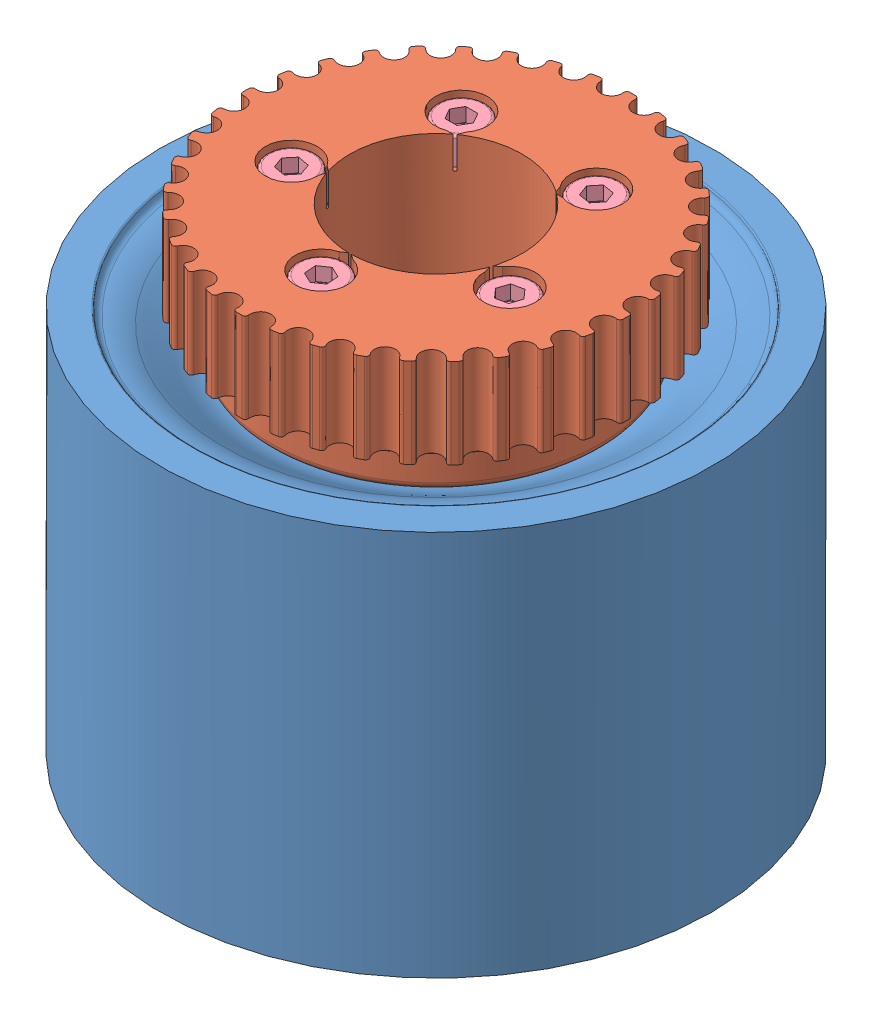
SolidWorks assembly Wheel Assy, configuration Standard. Lengths in mm.
Overall size (80 69 80).
13 component instances, 5 part files, 26 mates.
Components (placement in the parent):
- Orangatang Kegel 83mm Longboard Wheel-1: Orangatang Kegel 83mm Longboard Wheel [Default] at origin size (80 56 80)
- HTD Parametric Pulley-1: HTD Parametric Pulley [36T 13mm] at (0 31.6628 0) x (-0.809017 0 -0.587785) z (-0.587785 0 0.809017) size (56.01 36.18 56.01)
- Orangatang Kegel Flat Face-1: Orangatang Kegel Flat Face [Reshaped - to be tested] at (0 -25.3378 0) size (44 16.93 44)
- DIN 912 M4x60-1: DIN 912 M4x60 [DIN 912 M4 x 60] at (-9.7896 31.0628 -13.4742) x (0 -1 0) z (0 0 1) size (64 7 7)
- DIN 912 M4x60-2: DIN 912 M4x60 [DIN 912 M4 x 60] at (9.7896 31.0628 -13.4742) x (0 -1 0) z (-0.162886 0 0.986645) size (64 7 7)
- DIN 912 M4x60-3: DIN 912 M4x60 [DIN 912 M4 x 60] at (15.8398 30.8628 5.1467) x (0 -1 0) z (0.948955 0 0.315412) size (64 7 7)
- DIN 912 M4x60-4: DIN 912 M4x60 [DIN 912 M4 x 60] at (0 31.0628 16.655) x (0 -1 0) z (0.996968 0 -0.077808) size (64 7 7)
- DIN 912 M4x60-5: DIN 912 M4x60 [DIN 912 M4 x 60] at (-15.8398 31.0628 5.1467) x (0 -1 0) z (-0.173405 0 0.984851) size (64 7 7)
- prevailing torque nut style 1 insert_din-1: prevailing torque nut style 1 insert_din [DIN EN ISO 7040 - M4] at (-15.8398 -28.2378 5.1467) x (0.490805 0 -0.87127) z (0 -1 0) size (7 8.08 6)
- prevailing torque nut style 1 insert_din-2: prevailing torque nut style 1 insert_din [DIN EN ISO 7040 - M4] at (-9.7896 -28.2378 -13.4742) x (0.933211 0 -0.359329) z (0 -1 0) size (7 8.08 6)
- prevailing torque nut style 1 insert_din-3: prevailing torque nut style 1 insert_din [DIN EN ISO 7040 - M4] at (0 -28.2378 16.655) x (0.96783 0 -0.251605) z (0 -1 0) size (7 8.08 6)
- prevailing torque nut style 1 insert_din-4: prevailing torque nut style 1 insert_din [DIN EN ISO 7040 - M4] at (15.8398 -28.2378 5.1467) x (0.061225 0 -0.998124) z (0 -1 0) size (7 8.08 6)
- prevailing torque nut style 1 insert_din-5: prevailing torque nut style 1 insert_din [DIN EN ISO 7040 - M4] at (9.7896 -28.2378 -13.4742) x (0.981006 0 -0.193977) z (0 -1 0) size (7 8.08 6)
Mates (geometry in assembly coordinates):
- Konzentrisch1: concentric anti-aligned: cylinder of Orangatang Kegel 83mm Longboard Wheel-1 through (0 18.6628 0) axis (0 1 0) radius 11; cylinder of HTD Parametric Pulley-1 through (0 18.6628 0) axis (0 -1 0) radius 12.5
- Konzentrisch2: concentric aligned: cylinder of Orangatang Kegel 83mm Longboard Wheel-1 through (-15.0742 18.6628 -4.8979) axis (0 -1 0) radius 2.9; cylinder of HTD Parametric Pulley-1 through (-15.0742 31.6638 -4.8979) axis (0 -1 0) radius 2.85
- Deckungsgleich1: coincident anti-aligned: circle of Orangatang Kegel 83mm Longboard Wheel-1; circle of HTD Parametric Pulley-1
- Konzentrisch3: concentric anti-aligned: cylinder of Orangatang Kegel 83mm Longboard Wheel-1 through (0 18.6628 0) axis (0 1 0) radius 9.75; cylinder of Orangatang Kegel Flat Face-1 through (0 -32.3378 0) axis (0 -1 0) radius 12.5
- Konzentrisch4: concentric aligned: cylinder of Orangatang Kegel 83mm Longboard Wheel-1 through (-15.0742 18.6628 -4.8979) axis (0 -1 0) radius 2.9; cylinder of Orangatang Kegel Flat Face-1 through (-15.0742 -8.4032 -4.8979) axis (0 -1 0) radius 2.85
- Tangential1: tangent: circle of Orangatang Kegel 83mm Longboard Wheel-1; face of Orangatang Kegel Flat Face-1
- Konzentrisch6: concentric anti-aligned: cylinder of HTD Parametric Pulley-1 through (-9.7896 31.6628 -13.4742) axis (0 -1 0) radius 2.1; cylinder of DIN 912 M4x60-1 through (-9.7896 62.8128 -13.4742) axis (0 1 0) radius 2
- Konzentrisch7: concentric anti-aligned: cylinder of HTD Parametric Pulley-1 through (9.7896 31.6628 -13.4742) axis (0 -1 0) radius 2.1; cylinder of DIN 912 M4x60-2 through (9.7896 62.8128 -13.4742) axis (0 1 0) radius 2
- Konzentrisch8: concentric anti-aligned: cylinder of HTD Parametric Pulley-1 through (15.8398 31.6628 5.1467) axis (0 -1 0) radius 2.1; cylinder of DIN 912 M4x60-3 through (15.8398 62.6128 5.1467) axis (0 1 0) radius 2
- Konzentrisch9: concentric anti-aligned: cylinder of HTD Parametric Pulley-1 through (0 31.6628 16.655) axis (0 -1 0) radius 2.1; cylinder of DIN 912 M4x60-4 through (0 62.8128 16.655) axis (0 1 0) radius 2
- Konzentrisch10: concentric anti-aligned: cylinder of HTD Parametric Pulley-1 through (-15.8398 31.6628 5.1467) axis (0 -1 0) radius 2.1; cylinder of DIN 912 M4x60-5 through (-15.8398 62.8128 5.1467) axis (0 1 0) radius 2
- Deckungsgleich3: coincident anti-aligned: plane of HTD Parametric Pulley-1 through (0 27.0628 0) normal (0 1 0); plane of DIN 912 M4x60-1 through (-6.2896 27.0628 -13.4742) normal (0 -1 0)
- Deckungsgleich4: coincident anti-aligned: plane of HTD Parametric Pulley-1 through (0 27.0628 0) normal (0 1 0); plane of DIN 912 M4x60-5 through (-12.3929 27.0628 5.7536) normal (0 -1 0)
- Deckungsgleich5: coincident anti-aligned: plane of HTD Parametric Pulley-1 through (0 27.0628 0) normal (0 1 0); plane of DIN 912 M4x60-4 through (-0.2723 27.0628 13.1656) normal (0 -1 0)
- Deckungsgleich6: coincident aligned: plane of HTD Parametric Pulley-1 through (0 26.8628 0) normal (0 1 0); circle of DIN 912 M4x60-3
- Deckungsgleich7: coincident anti-aligned: plane of HTD Parametric Pulley-1 through (0 27.0628 0) normal (0 1 0); plane of DIN 912 M4x60-2 through (13.2428 27.0628 -12.9041) normal (0 -1 0)
- Konzentrisch11: concentric anti-aligned: cylinder of DIN 912 M4x60-1 through (-9.7896 62.8128 -13.4742) axis (0 1 0) radius 2; cylinder of DIN EN ISO 7040 M4-2 through (-9.7896 -25.3378 -13.4742) axis (0 -1 0) radius 1.65
- Konzentrisch12: concentric anti-aligned: cylinder of DIN 912 M4x60-5 through (-15.8398 62.8128 5.1467) axis (0 1 0) radius 2; cylinder of DIN EN ISO 7040 M4-1 through (-15.8398 -25.3378 5.1467) axis (0 -1 0) radius 1.65
- Konzentrisch13: concentric anti-aligned: cylinder of DIN EN ISO 7040 M4-3 through (0 -25.3378 16.655) axis (0 -1 0) radius 1.65; cylinder of DIN 912 M4x60-4 through (0 62.8128 16.655) axis (0 1 0) radius 2
- Konzentrisch14: concentric anti-aligned: cylinder of DIN 912 M4x60-3 through (15.8398 62.6128 5.1467) axis (0 1 0) radius 2; cylinder of DIN EN ISO 7040 M4-4 through (15.8398 -25.3378 5.1467) axis (0 -1 0) radius 1.65
- Konzentrisch15: concentric anti-aligned: cylinder of DIN EN ISO 7040 M4-5 through (9.7896 -25.3378 -13.4742) axis (0 -1 0) radius 1.65; cylinder of DIN 912 M4x60-2 through (9.7896 62.8128 -13.4742) axis (0 1 0) radius 2
- Deckungsgleich8: coincident aligned: plane of DIN EN ISO 7040 M4-4 through (19.8737 -25.3378 5.3941) normal (0 1 0); plane of DIN EN ISO 7040 M4-5 through (10.5735 -25.3378 -9.5095) normal (0 1 0)
- Deckungsgleich9: coincident aligned: plane of DIN EN ISO 7040 M4-2 through (-8.3374 -25.3378 -9.7027) normal (0 1 0); plane of DIN EN ISO 7040 M4-5 through (10.5735 -25.3378 -9.5095) normal (0 1 0)
- Deckungsgleich10: coincident aligned: plane of DIN EN ISO 7040 M4-3 through (1.0168 -25.3378 20.5664) normal (0 1 0); plane of DIN EN ISO 7040 M4-5 through (10.5735 -25.3378 -9.5095) normal (0 1 0)
- Deckungsgleich11: coincident aligned: plane of DIN EN ISO 7040 M4-1 through (-12.3187 -25.3378 7.1302) normal (0 1 0); plane of DIN EN ISO 7040 M4-5 through (10.5735 -25.3378 -9.5095) normal (0 1 0)
- Deckungsgleich12: coincident anti-aligned: plane of Orangatang Kegel Flat Face-1 through (-22 -25.3378 0) normal (0 -1 0); plane of DIN EN ISO 7040 M4-5 through (10.5735 -25.3378 -9.5095) normal (0 1 0)
